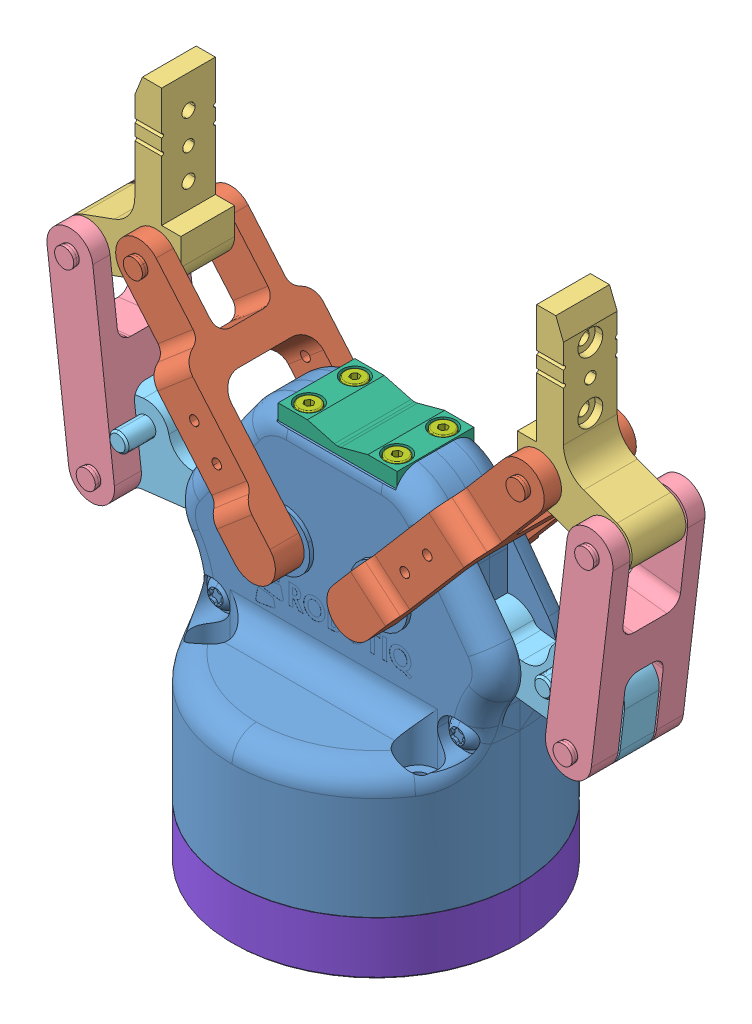
SolidWorks assembly 2-Finger_85_Adaptive_Gripper-opened, configuration 默认. Lengths in mm.
Overall size (155.27 153.74 75).
13 component instances, 8 part files, 3 mates.
Components (placement in the parent):
- 2-Finger_85_Adaptive_Gripper-opened.STEP-1: 2-Finger_85_Adaptive_Gripper-opened.STEP [默认] at origin size (155.27 146.85 75)
  - Group1^2-Finger_85_Adaptive_Gripper.STEP-1: Group1^2-Finger_85_Adaptive_Gripper.STEP [默认] at origin size (89.61 93.67 75)
  - Group2^2-Finger_85_Adaptive_Gripper.STEP-1: Group2^2-Finger_85_Adaptive_Gripper.STEP [默认] at (-12.7 -28.58 0) x (0.759872 0.650073 0) z (0 0 1) size (12 69.15 39)
  - Group2^2-Finger_85_Adaptive_Gripper.STEP-2: Group2^2-Finger_85_Adaptive_Gripper.STEP [默认] at (12.7 -28.58 0) x (0.759872 -0.650073 0) z (0 0 1) size (12 69.15 39)
  - Group3^2-Finger_85_Adaptive_Gripper.STEP-1: Group3^2-Finger_85_Adaptive_Gripper.STEP [默认] at (0.4488 0.3881 0) x (1 0 0) z (0 0 1) size (29.9 50.51 15)
  - Group3^2-Finger_85_Adaptive_Gripper.STEP-2: Group3^2-Finger_85_Adaptive_Gripper.STEP [默认] at (-0.4488 0.3881 0) x (-1 0 0) z (0 0 -1) size (29.9 50.51 15)
  - Group4^2-Finger_85_Adaptive_Gripper.STEP-1: Group4^2-Finger_85_Adaptive_Gripper.STEP [默认] at (0.3627 -0.3196 0) x (0.999946 -0.010382 0) z (0 0 1) size (18.11 59.12 27)
  - Group4^2-Finger_85_Adaptive_Gripper.STEP-2: Group4^2-Finger_85_Adaptive_Gripper.STEP [默认] at (131.9261 -16.0902 0) x (0.969481 -0.245165 0) z (0 0 1) size (18.11 59.12 27)
  - Group5^2-Finger_85_Adaptive_Gripper.STEP-1: Group5^2-Finger_85_Adaptive_Gripper.STEP [默认] at (-0.3627 -0.3196 0) x (0.999946 0.010382 0) z (0 0 1) size (46.27 22.95 24.01)
  - Group5^2-Finger_85_Adaptive_Gripper.STEP-2: Group5^2-Finger_85_Adaptive_Gripper.STEP [默认] at (0.3627 -0.3196 0) x (-0.999946 0.010382 0) z (0 0 -1) size (46.27 22.95 24.01)
  - Group6^2-Finger_85_Adaptive_Gripper.STEP-1: Group6^2-Finger_85_Adaptive_Gripper.STEP [默认] at (0 -4 0) x (1 0 0) z (0 1 0) size (31 20 4)
  - Group7^2-Finger_85_Adaptive_Gripper.STEP-1: Group7^2-Finger_85_Adaptive_Gripper.STEP [默认] at origin size (28.5 12 17.5)
- AGC-CPL-062-002-1: AGC-CPL-062-002 [默认] at (0 -93.8875 0) x (-1 0 0) z (0 1 0) size (75 75 13.9)
Mates (geometry in assembly coordinates):
- 同心1: concentric: cylinder of ? through (0 -17.9786 0) axis (0 -1 0) radius 37.5; cylinder of AGC-CPL-062-002-1 through (0 -100.8875 0) axis (0 1 0) radius 37.5
- 同心2: concentric: cylinder of ? through (30.5 -73.65 0) axis (0 1 0) radius 2; cylinder of AGC-CPL-062-002-1 through (30.5 -89.8875 0) axis (0 1 0) radius 2
- 重合1: coincident: plane of ? through (0 -89.8875 0) normal (0 -1 0); plane of AGC-CPL-062-002-1 through (0 -89.8875 0) normal (0 1 0)
